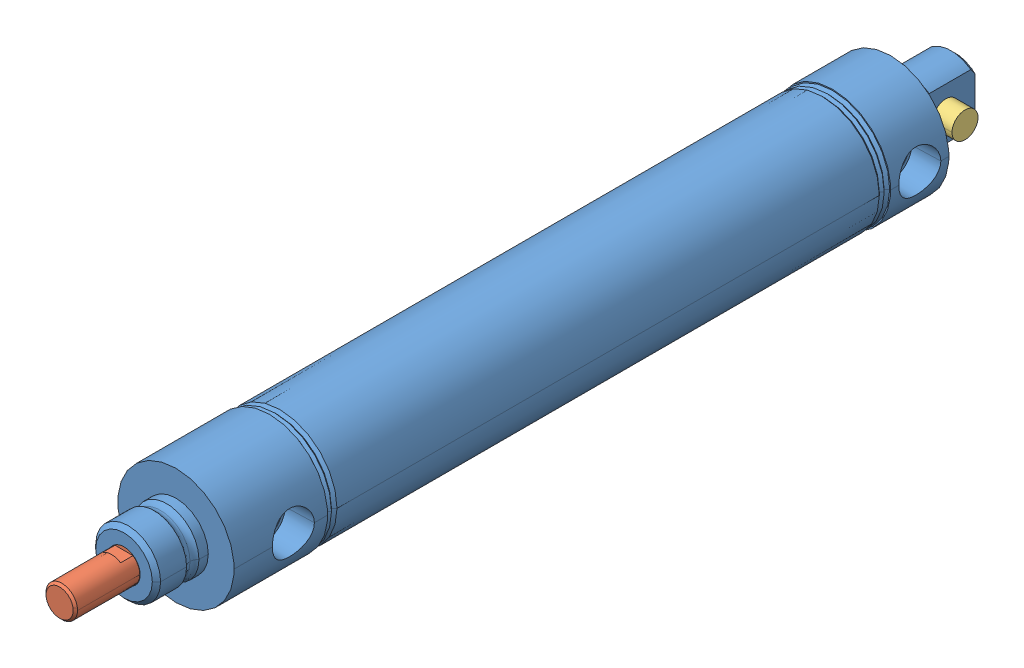
SolidWorks assembly A17040DP.step, configuration Default. Lengths in mm.
Overall size (30.5 30.5 218.95).
3 component instances, 3 part files, 0 mates.
Components (placement in the parent):
- A17040DP-MainBody.step-1: A17040DP-MainBody.step [Default] x (0 0 -1) z (1 0 0) size (203.2 28.45 28.45)
- A17040DP-Rod.step-1: A17040DP-Rod.step [Default] at (0 0 745.5499) x (0 0 -1) z (0.990171 0.139861 0) size (172.97 26.99 26.99)
- A17040DP-PIN.step-1: A17040DP-PIN.step [Default] at (0 0 -199.136) x (0 0 -1) z (1 0 0) size (6.35 6.35 19.05)
